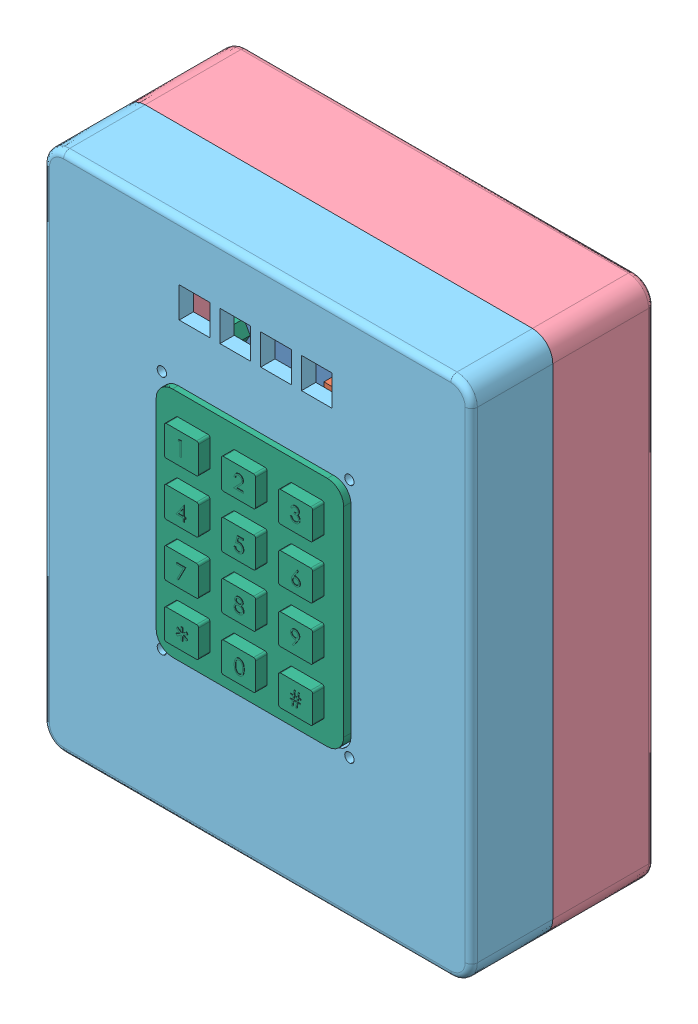
SolidWorks assembly keyInput_, configuration Default. Lengths in mm.
Overall size (105 128 60.99).
101 component instances, 25 part files, 8 mates.
Components (placement in the parent):
- keyInput1.step-1: keyInput1.step [Default] at origin size (85 80 39.05)
  - Board.step-1: Board.step [Default] at origin size (85 80 0.41)
    - Open CASCADE STEP translator 6.8 2.1.1.step-1: Open CASCADE STEP translator 6.8 2.1.1.step [Default] at (0 0 -0.4115) size (85 80 0.41)
  - U2.step-1: U2.step [Default] at origin size (10.2 4.7 20.55)
    - 5932290336.step-1: 5932290336.step [Default] at (7.76 15.285 17.95) size (9.9 1.35 1)
      - Extruded.step-1: Extruded.step [Default] at origin size (9.9 1.35 1)
    - 5932290176.step-1: 5932290176.step [Default] at (11.135 15.285 16.15) size (3.15 1.35 0.36)
      - Extruded-0.step-1: Extruded-0.step [Default] at origin size (3.15 1.35 0.36)
    - 5932290176.step-2: 5932290176.step [Default] at (4.385 15.285 16.15) size (3.15 1.35 0.36)
      - Extruded-0.step-1: Extruded-0.step [Default] at origin size (3.15 1.35 0.36)
    - 5932289936.step-1: 5932289936.step [Default] at (11.135 15.285 15.8) size (3.15 1.35 0.35)
      - Extruded-1.step-1: Extruded-1.step [Default] at origin size (3.15 1.35 0.35)
    - 5932289936.step-2: 5932289936.step [Default] at (4.385 15.285 15.8) size (3.15 1.35 0.35)
      - Extruded-1.step-1: Extruded-1.step [Default] at origin size (3.15 1.35 0.35)
    - 5932289696.step-1: 5932289696.step [Default] at (11.1177 15.285 16.5) size (3.18 1.35 0.34)
      - Extruded-2.step-1: Extruded-2.step [Default] at origin size (3.18 1.35 0.34)
    - 5932289696.step-2: 5932289696.step [Default] at (4.4023 15.285 16.5) size (3.18 1.35 0.34)
      - Extruded-2.step-1: Extruded-2.step [Default] at origin size (3.18 1.35 0.34)
    - 5932289696.step-3: 5932289696.step [Default] at (11.1177 15.285 15.46) size (3.18 1.35 0.34)
      - Extruded-2.step-1: Extruded-2.step [Default] at origin size (3.18 1.35 0.34)
    - 5932289696.step-4: 5932289696.step [Default] at (4.4023 15.285 15.46) size (3.18 1.35 0.34)
      - Extruded-2.step-1: Extruded-2.step [Default] at origin size (3.18 1.35 0.34)
    - 5932289296.step-1: 5932289296.step [Default] at (11.0665 15.285 16.84) size (3.29 1.35 0.32)
      - Extruded-3.step-1: Extruded-3.step [Default] at origin size (3.29 1.35 0.32)
    - 5932289296.step-2: 5932289296.step [Default] at (4.4535 15.285 16.84) size (3.29 1.35 0.32)
      - Extruded-3.step-1: Extruded-3.step [Default] at origin size (3.29 1.35 0.32)
    - 5932289056.step-1: 5932289056.step [Default] at (11.0665 15.285 15.15) size (3.29 1.35 0.32)
      - Extruded-4.step-1: Extruded-4.step [Default] at origin size (3.29 1.35 0.32)
    - 5932289056.step-2: 5932289056.step [Default] at (4.4535 15.285 15.15) size (3.29 1.35 0.32)
      - Extruded-4.step-1: Extruded-4.step [Default] at origin size (3.29 1.35 0.32)
    - 5932288816.step-1: 5932288816.step [Default] at (10.9833 15.285 17.15) size (3.45 1.35 0.28)
      - Extruded-5.step-1: Extruded-5.step [Default] at origin size (3.45 1.35 0.28)
    - 5932288816.step-2: 5932288816.step [Default] at (4.5367 15.285 17.15) size (3.45 1.35 0.28)
      - Extruded-5.step-1: Extruded-5.step [Default] at origin size (3.45 1.35 0.28)
    - 5932288576.step-1: 5932288576.step [Default] at (10.9833 15.285 14.88) size (3.45 1.35 0.27)
      - Extruded-6.step-1: Extruded-6.step [Default] at origin size (3.45 1.35 0.27)
    - 5932288576.step-2: 5932288576.step [Default] at (4.5367 15.285 14.88) size (3.45 1.35 0.27)
      - Extruded-6.step-1: Extruded-6.step [Default] at origin size (3.45 1.35 0.27)
    - 5932288336.step-1: 5932288336.step [Default] at (10.8714 15.285 17.42) size (3.68 1.35 0.23)
      - Extruded-7.step-1: Extruded-7.step [Default] at origin size (3.68 1.35 0.23)
    - 5932288336.step-2: 5932288336.step [Default] at (4.6486 15.285 17.42) size (3.68 1.35 0.23)
      - Extruded-7.step-1: Extruded-7.step [Default] at origin size (3.68 1.35 0.23)
    - 5932288336.step-3: 5932288336.step [Default] at (10.8714 15.285 14.65) size (3.68 1.35 0.23)
      - Extruded-7.step-1: Extruded-7.step [Default] at origin size (3.68 1.35 0.23)
    - 5932288336.step-4: 5932288336.step [Default] at (4.6486 15.285 14.65) size (3.68 1.35 0.23)
      - Extruded-7.step-1: Extruded-7.step [Default] at origin size (3.68 1.35 0.23)
    - 5932287936.step-1: 5932287936.step [Default] at (10.735 15.285 17.65) size (3.95 1.35 0.17)
      - Extruded-8.step-1: Extruded-8.step [Default] at origin size (3.95 1.35 0.17)
    - 5932287936.step-2: 5932287936.step [Default] at (4.785 15.285 17.65) size (3.95 1.35 0.17)
      - Extruded-8.step-1: Extruded-8.step [Default] at origin size (3.95 1.35 0.17)
    - 5932287696.step-1: 5932287696.step [Default] at (10.735 15.285 14.49) size (3.95 1.35 0.17)
      - Extruded-9.step-1: Extruded-9.step [Default] at origin size (3.95 1.35 0.17)
    - 5932287696.step-2: 5932287696.step [Default] at (4.785 15.285 14.49) size (3.95 1.35 0.17)
      - Extruded-9.step-1: Extruded-9.step [Default] at origin size (3.95 1.35 0.17)
    - 5932287456.step-1: 5932287456.step [Default] at (10.5794 15.285 17.81) size (4.26 1.35 0.11)
      - Extruded-10.step-1: Extruded-10.step [Default] at origin size (4.26 1.35 0.11)
    - 5932287456.step-2: 5932287456.step [Default] at (4.9406 15.285 17.81) size (4.26 1.35 0.11)
      - Extruded-10.step-1: Extruded-10.step [Default] at origin size (4.26 1.35 0.11)
    - 5932287456.step-3: 5932287456.step [Default] at (10.5794 15.285 14.38) size (4.26 1.35 0.11)
      - Extruded-10.step-1: Extruded-10.step [Default] at origin size (4.26 1.35 0.11)
    - 5932287456.step-4: 5932287456.step [Default] at (4.9406 15.285 14.38) size (4.26 1.35 0.11)
      - Extruded-10.step-1: Extruded-10.step [Default] at origin size (4.26 1.35 0.11)
    - 5932287056.step-1: 5932287056.step [Default] at (10.4106 15.285 17.92) size (4.6 1.35 0.03)
      - Extruded-11.step-1: Extruded-11.step [Default] at origin size (4.6 1.35 0.03)
    - 5932287056.step-2: 5932287056.step [Default] at (5.1094 15.285 17.92) size (4.6 1.35 0.03)
      - Extruded-11.step-1: Extruded-11.step [Default] at origin size (4.6 1.35 0.03)
    - 5932286816.step-1: 5932286816.step [Default] at (10.4106 15.285 14.35) size (4.6 1.35 0.04)
      - Extruded-12.step-1: Extruded-12.step [Default] at origin size (4.6 1.35 0.04)
    - 5932286816.step-2: 5932286816.step [Default] at (5.1094 15.285 14.35) size (4.6 1.35 0.04)
      - Extruded-12.step-1: Extruded-12.step [Default] at origin size (4.6 1.35 0.04)
    - 5932286576.step-1: 5932286576.step [Default] at (7.76 15.285 12.2) size (9.9 1.35 2.15)
      - Extruded-13.step-1: Extruded-13.step [Default] at origin size (9.9 1.35 2.15)
    - 5932286416.step-1: 5932286416.step [Default] at (7.76 13.61 3) size (10.2 4.7 9.2)
      - Extruded-14.step-1: Extruded-14.step [Default] at origin size (10.2 4.7 9.2)
    - 5932286256.step-1: 5932286256.step [Default] at (10.3 13.3 -1.6) size (0.8 0.53 1.6)
      - Extruded-15.step-1: Extruded-15.step [Default] at origin size (0.8 0.53 1.6)
    - 5932286096.step-1: 5932286096.step [Default] at (10.3 13.3 0) size (1.52 0.53 3)
      - Extruded-16.step-1: Extruded-16.step [Default] at origin size (1.52 0.53 3)
    - 5932286256.step-2: 5932286256.step [Default] at (7.76 13.3 -1.6) size (0.8 0.53 1.6)
      - Extruded-15.step-1: Extruded-15.step [Default] at origin size (0.8 0.53 1.6)
    - 5932286096.step-2: 5932286096.step [Default] at (7.76 13.3 0) size (1.52 0.53 3)
      - Extruded-16.step-1: Extruded-16.step [Default] at origin size (1.52 0.53 3)
    - 5932286256.step-3: 5932286256.step [Default] at (5.22 13.3 -1.6) size (0.8 0.53 1.6)
      - Extruded-15.step-1: Extruded-15.step [Default] at origin size (0.8 0.53 1.6)
    - 5932286096.step-3: 5932286096.step [Default] at (5.22 13.3 0) size (1.52 0.53 3)
      - Extruded-16.step-1: Extruded-16.step [Default] at origin size (1.52 0.53 3)
  - U1.step-1: U1.step [Default] at origin size (35.3 7.2 4.58)
    - 5938057616.step-1: 5938057616.step [Default] at (44.44 37.44 0) size (35.3 7.2 4.58)
      - Extruded-17.step-1: Extruded-17.step [Default] at origin size (35.3 7.2 4.58)
  - LED4.step-1: LED4.step [Default] at origin size (5.45 5.9 35.6)
    - WP7113.step-1: WP7113.step [Default] at (27.5 72.2001 6.9) x (1 0 0) z (0 -1 0) size (5.45 35.6 5.9)
  - LED3.step-1: LED3.step [Default] at origin size (5.45 5.9 35.6)
    - WP7113.step-1: WP7113.step [Default] at (37.5 72.2001 6.9) x (1 0 0) z (0 -1 0) size (5.45 35.6 5.9)
  - LED2.step-1: LED2.step [Default] at origin size (5.45 5.9 35.6)
    - WP7113.step-1: WP7113.step [Default] at (47.5 72.2001 6.9) x (1 0 0) z (0 -1 0) size (5.45 35.6 5.9)
  - LED1.step-1: LED1.step [Default] at origin size (5.45 5.9 35.6)
    - WP7113.step-1: WP7113.step [Default] at (57.5 72.2001 6.9) x (1 0 0) z (0 -1 0) size (5.45 35.6 5.9)
- test_bottom-2: test_bottom [Default] at (13.7677 45.3924 -8.406) x (-1 0 0) z (0 1 0) size (105 25 128)
- test_top-1: test_top [Default] at (67.8129 7.8546 16.594) x (1 0 0) z (0 -1 0) size (105 36.34 128)
- Keypad 3x4.step-1: Keypad 3x4.step [Default] at (42.0733 25.8924 18.094) x (1 0 0) z (0 -1 0) size (52.35 22.8 69.75)
- 9V Battery Holder-3: 9V Battery Holder [Default] at (15.3753 -1.2073 15.396) x (0 -1 0) z (1 0 0) size (30 20 54)
Mates (geometry in assembly coordinates):
- Coincident2: coincident: plane of test_bottom-2 through (13.7677 45.3924 16.594) normal (0 0 1); plane of test_top-1 through (67.8129 7.8546 16.594) normal (0 0 -1)
- Parallel2: parallel: plane of test_bottom-2 through (94.9733 -38.0076 16.594) normal (0 -1 0); plane of test_top-1 through (-10.0267 -38.0076 36.594) normal (0 -1 0)
- Coincident5: coincident: line of test_bottom-2 through (-5.0267 -38.0076 16.594) axis (0 0 -1); cylinder of test_top-1 through (-5.0267 -33.0076 36.594) axis (0 0 -1) radius 5
- Coincident6: coincident: plane of test_top-1 through (67.8129 7.8546 33.094) normal (0 0 -1); plane of Keypad 3x4.step-1 through (20.5733 53.8924 33.094) normal (0 0 1)
- Coincident9: coincident: plane of test_top-1 through (19.0733 54.3924 36.594) normal (1 0 0); plane of Keypad 3x4.step-1 through (19.0733 1.3924 37.994) normal (-1 0 0)
- Coincident10: coincident: plane of test_top-1 through (67.8129 7.8546 33.094) normal (0 0 -1); plane of Keypad 3x4.step-1 through (20.5733 53.8924 33.094) normal (0 0 1)
- Concentric3: concentric: cylinder of test_bottom-2 through (-5.0267 -33.0076 16.594) axis (0 0 -1) radius 5; cylinder of test_top-1 through (-5.0267 -33.0076 36.594) axis (0 0 -1) radius 5
- Coincident12: coincident: plane of test_top-1 through (65.4733 54.3924 36.594) normal (0 -1 0); plane of Keypad 3x4.step-1 through (23.0733 54.3924 37.994) normal (0 1 0)
